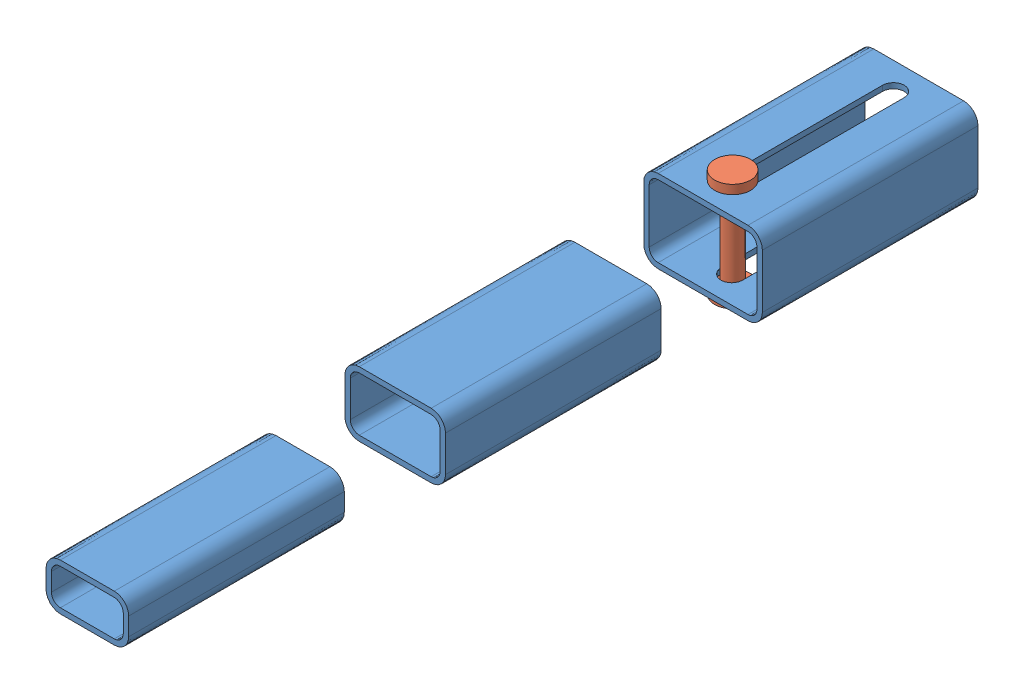
SolidWorks assembly advancedmechanicalmates, configuration Default. Lengths in mm.
Overall size (66 60 462.64).
4 component instances, 2 part files, 9 mates.
Components (placement in the parent):
- advancedmechanicalmates-1: advancedmechanicalmates [Large] at (-9.156 76.245 111.3234) size (66 46 120)
- advancedmechanicalmates-2: advancedmechanicalmates [Medium] at (-14.156 81.245 282.6456) size (56 36 120)
- advancedmechanicalmates-3: advancedmechanicalmates [Small] at (-19.156 86.245 453.9678) size (46 26 120)
- pin-1: pin [Default] at (-9.156 77.1933 155.8129) x (-0.445577 0 -0.895244) z (0 1 0) size (20 20 60)
Mates (geometry in assembly coordinates):
- Width1: width anti-aligned: plane of advancedmechanicalmates-1 through (-35.1043 97.1933 171.3234) normal (0 -1 0); plane of advancedmechanicalmates-2 through (-35.1043 57.1933 171.3234) normal (0 1 0); plane of advancedmechanicalmates-1 through (-30.1043 95.1933 342.6456) normal (0 1 0); plane of advancedmechanicalmates-2 through (-30.1043 59.1933 342.6456) normal (0 -1 0)
- Width2: width anti-aligned: plane of advancedmechanicalmates-1 through (-40.1043 92.1933 171.3234) normal (1 0 0); plane of advancedmechanicalmates-2 through (19.8957 92.1933 171.3234) normal (-1 0 0); plane of advancedmechanicalmates-1 through (-38.1043 87.1933 342.6456) normal (-1 0 0); plane of advancedmechanicalmates-2 through (17.8957 87.1933 342.6456) normal (1 0 0)
- Width3: width anti-aligned: plane of advancedmechanicalmates-2 through (-35.1043 87.1933 342.6456) normal (1 0 0); plane of advancedmechanicalmates-3 through (14.8957 87.1933 342.6456) normal (-1 0 0); plane of advancedmechanicalmates-2 through (-33.1043 82.1933 513.9678) normal (-1 0 0); plane of advancedmechanicalmates-3 through (12.8957 82.1933 513.9678) normal (1 0 0)
- Width4: width aligned: plane of advancedmechanicalmates-2 through (-30.1043 62.1933 342.6456) normal (0 1 0); plane of advancedmechanicalmates-3 through (-30.1043 92.1933 342.6456) normal (0 -1 0); plane of advancedmechanicalmates-2 through (-25.1043 90.1933 513.9678) normal (0 1 0); plane of advancedmechanicalmates-3 through (-25.1043 64.1933 513.9678) normal (0 -1 0)
- Coincident11: coincident aligned: plane of advancedmechanicalmates-1 through (14.8957 62.1933 171.3234) normal (0 0 1); plane of advancedmechanicalmates-2 through (9.8957 67.1933 171.3234) normal (0 0 1)
- Coincident12: coincident aligned: plane of advancedmechanicalmates-2 through (9.8957 67.1933 171.3234) normal (0 0 1); plane of advancedmechanicalmates-3 through (4.8957 72.1933 171.3234) normal (0 0 1)
- Linear/Linear Coupler1: linear coupler = 1 : 2 mm: plane of advancedmechanicalmates-2 through (9.8957 67.1933 342.6456) normal (0 0 1); plane of advancedmechanicalmates-3 through (4.8957 72.1933 513.9678) normal (0 0 1)
- Slot2: slot anti-aligned: cylinder of pin-1 through (-9.156 102.1933 155.8129) axis (0 -1 0) radius 5; plane of advancedmechanicalmates-1 through (-3.156 54.1933 66.3234) normal (-1 0 0); cylinder of advancedmechanicalmates-1 through (-9.156 54.1933 156.3234) axis (0 1 0) radius 6
- Width6: width anti-aligned: plane of pin-1 through (-9.156 102.1933 155.8129) normal (0 -1 0); plane of advancedmechanicalmates-1 through (-9.156 52.1933 155.8129) normal (0 1 0); plane of pin-1 through (-35.1043 100.1933 171.3234) normal (0 1 0); plane of advancedmechanicalmates-1 through (-35.1043 54.1933 171.3234) normal (0 -1 0)
